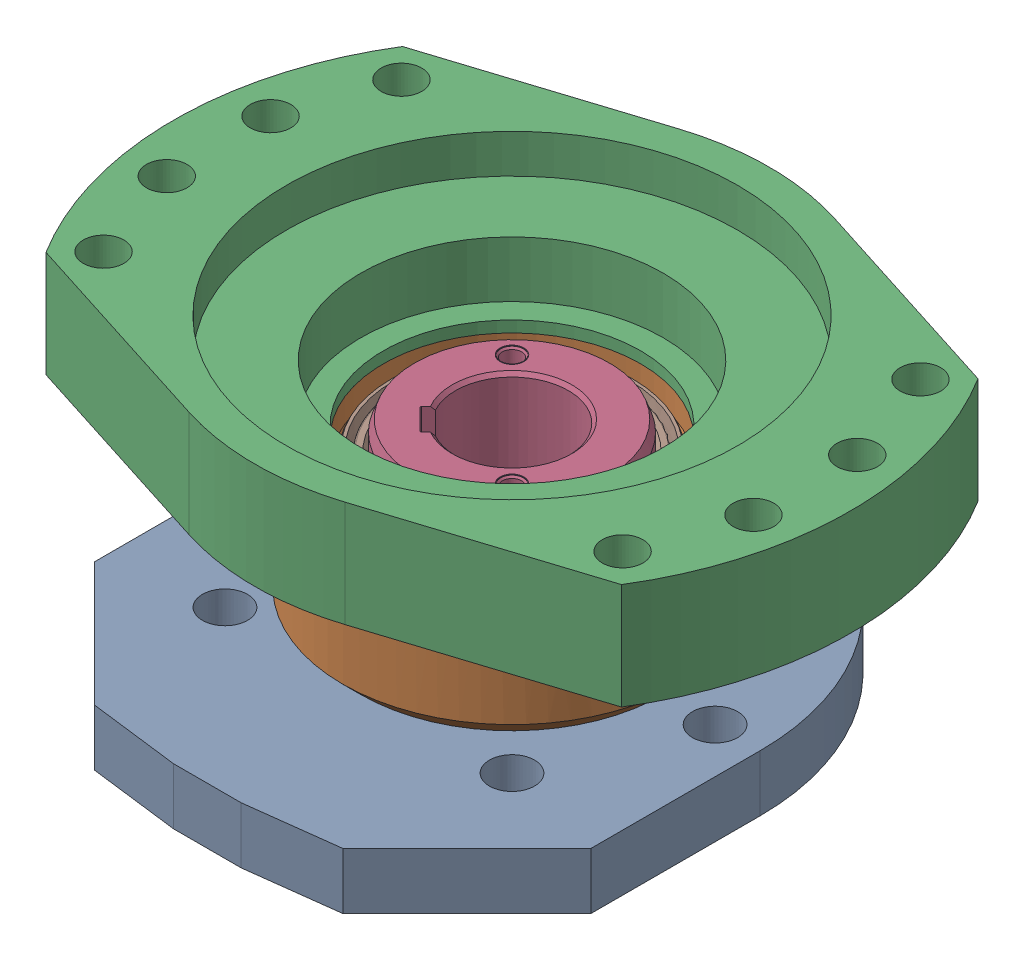
SolidWorks assembly g1_3_1_1_1, configuration 默认. Lengths in mm.
Overall size (300 165.8 249).
13 component instances, 8 part files, 0 mates.
Components (placement in the parent):
- g1_3_1_1_1_1-1: g1_3_1_1_1_1 [默认] at origin size (300 154 249)
  - g1_3_1_1_1_1-1_af0-1: g1_3_1_1_1_1-1_af0 [默认] at origin size (220 42 245)
  - g1_3_1_1_1_1-2_af0-1: g1_3_1_1_1_1-2_af0 [默认] at (0 50 0) size (150 65 150)
  - g1_3_1_1_1_1-3_af0-1: g1_3_1_1_1_1-3_af0 [默认] at (0 140 0) size (300 47 228)
- g1_3_1_1_1-2-1: g1_3_1_1_1-2 [默认] at (0 122.2 0) x (0.707107 0 0.707107) z (0.707107 0 -0.707107) size (90 126 90)
- g1_3_1_1_1-1-1: g1_3_1_1_1-1 [默认] at (0 77 0) x (0 1 0) z (0 0 1) size (20 110 110)
- b90x110x12_gb9877_1-1: b90x110x12_gb9877_1 [默认] at (0 66.9 0) size (108.6 17.9 108.6)
  - b90x110x12_gb9877_1_rubber-1: b90x110x12_gb9877_1_rubber [默认] at origin size (108.6 12 108.6)
  - b90x110x12_gb9877_1_frame-1: b90x110x12_gb9877_1_frame [默认] at (0 -2.4 0) x (-1 0 0) z (0 0 1) size (107.2 9.5 107.2)
- b90x110x12_gb9877_1-2: b90x110x12_gb9877_1 [默认] at (0 104.8 0) size (108.6 17.9 108.6)
  - b90x110x12_gb9877_1_rubber-1: b90x110x12_gb9877_1_rubber [默认] at origin size (108.6 12 108.6)
  - b90x110x12_gb9877_1_frame-1: b90x110x12_gb9877_1_frame [默认] at (0 -2.4 0) x (-1 0 0) z (0 0 1) size (107.2 9.5 107.2)
- 80_gb894_1-1: 80_gb894_1 [默认] at (-2.4 11.1 -38.1746) x (1 0 0) z (0 -1 0) size (85.83 90.87 2.5)
